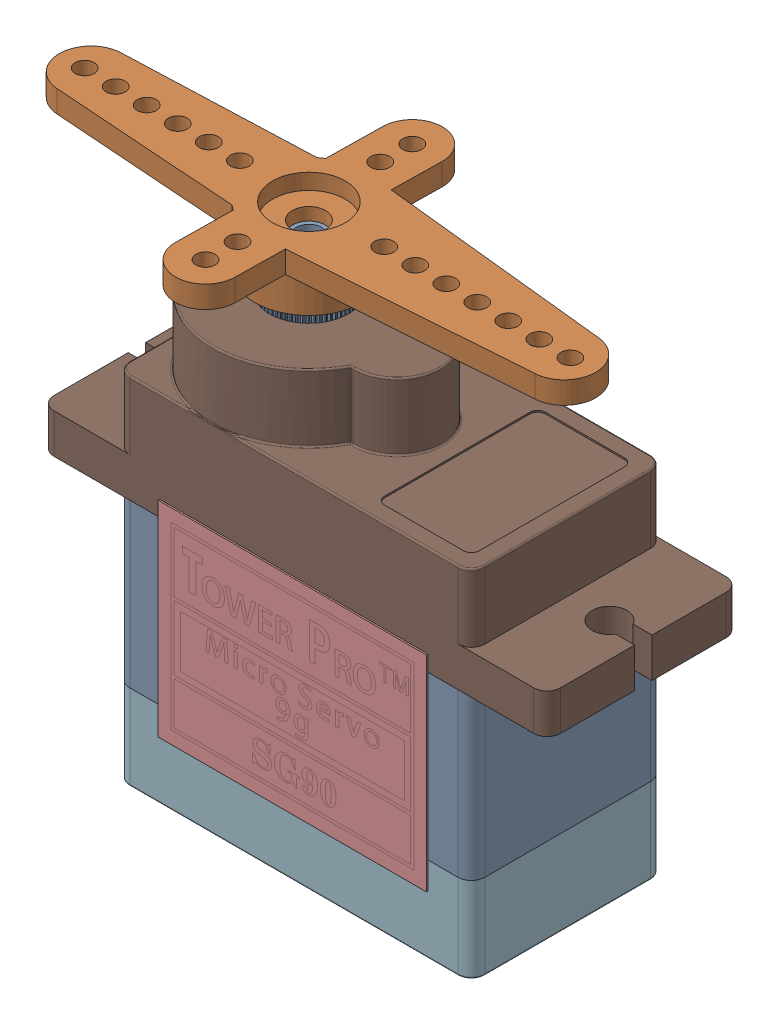
SolidWorks assembly SG90, configuration Predeterminado. Lengths in mm.
Overall size (37.38 31.75 17.26).
2 component instances, 2 part files, 2 mates.
Components (placement in the parent):
- Servo SG90-1: Servo SG90 [Peça] at (-1.7753 -3.0245 6.2) size (32.1 29.95 12.4)
- Brazo de servo SG90- Estrella 2-1: Brazo de servo SG90- Estrella 2 [Peça] at (-6.9253 18.0755 6.2) x (0.999866 0 0.016344) z (-0.016344 0 0.999866) size (34.5 3.8 16.7)
Mates (geometry in assembly coordinates):
- Concéntrica1: concentric aligned: circle of SG90 - Micro Servo 9g - Tower Pro.1-1; cylinder of SG90 - Micro Servo 9g - Tower Pro.4-1 through (-6.9253 18.0755 6.2) axis (0 1 0) radius 1.05
- Coincidente1: coincident anti-aligned: plane of SG90 - Micro Servo 9g - Tower Pro.1-1 through (-6.9253 16.2755 6.2) normal (0 1 0); plane of SG90 - Micro Servo 9g - Tower Pro.4-1 through (-6.9253 16.2755 6.2) normal (0 -1 0)
